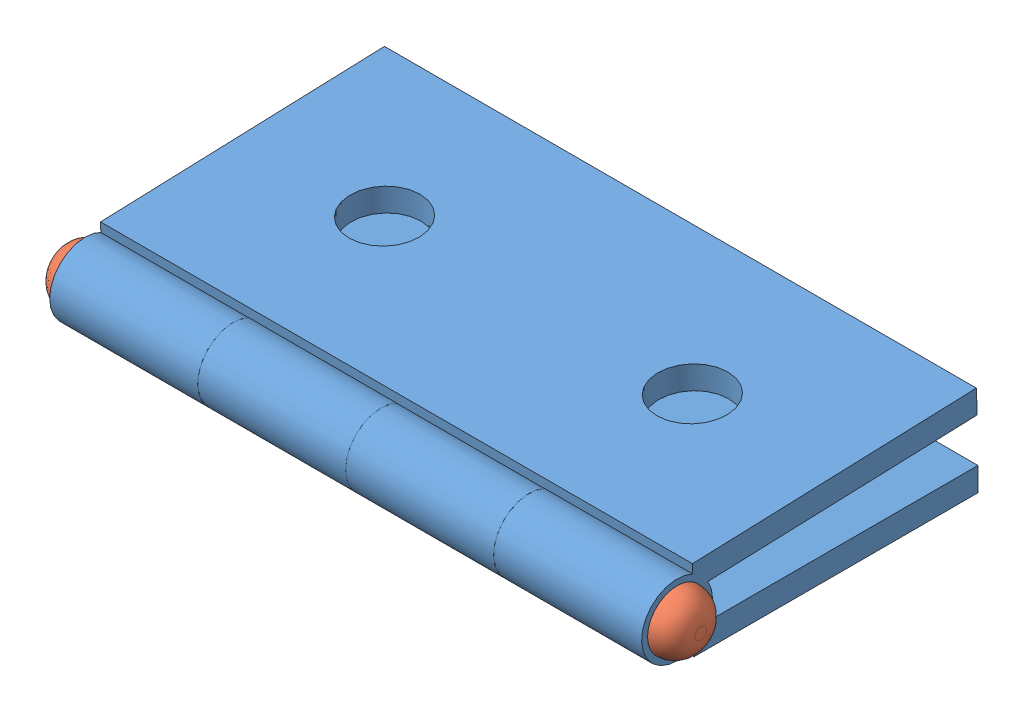
SolidWorks assembly hinge hang, configuration Default. Lengths in mm.
Overall size (27 4.86 15.6).
3 component instances, 2 part files, 4 mates.
Components (placement in the parent):
- hinge-1: hinge [Default] at (-3.4682 11.0876 24.4198) size (25 3 15.5)
- hinge-2: hinge [Default] at (21.5318 14.5258 24.4807) x (-1 0 0) z (0 -0.035419 0.999373) size (25 3 15.5)
- hinge spindle-1: hinge spindle [Default] at (21.5318 12.7947 25.1269) x (0 0.974188 -0.225738) z (0 0.225738 0.974188) size (2.5 27 2.5)
Mates (geometry in assembly coordinates):
- Concentric2: concentric anti-aligned: cylinder of hinge-1 through (15.2818 12.7947 25.1269) axis (-1 0 0) radius 1; cylinder of hinge spindle-1 through (-3.4682 12.7947 25.1269) axis (1 0 0) radius 1
- Coincident2: coincident anti-aligned: circle of hinge-1; circle of hinge spindle-1
- Coincident3: coincident anti-aligned: circle of hinge-2; cylinder of hinge spindle-1 through (-3.4682 12.7947 25.1269) axis (1 0 0) radius 1
- Coincident4: coincident aligned: circle of hinge-2; circle of hinge spindle-1
